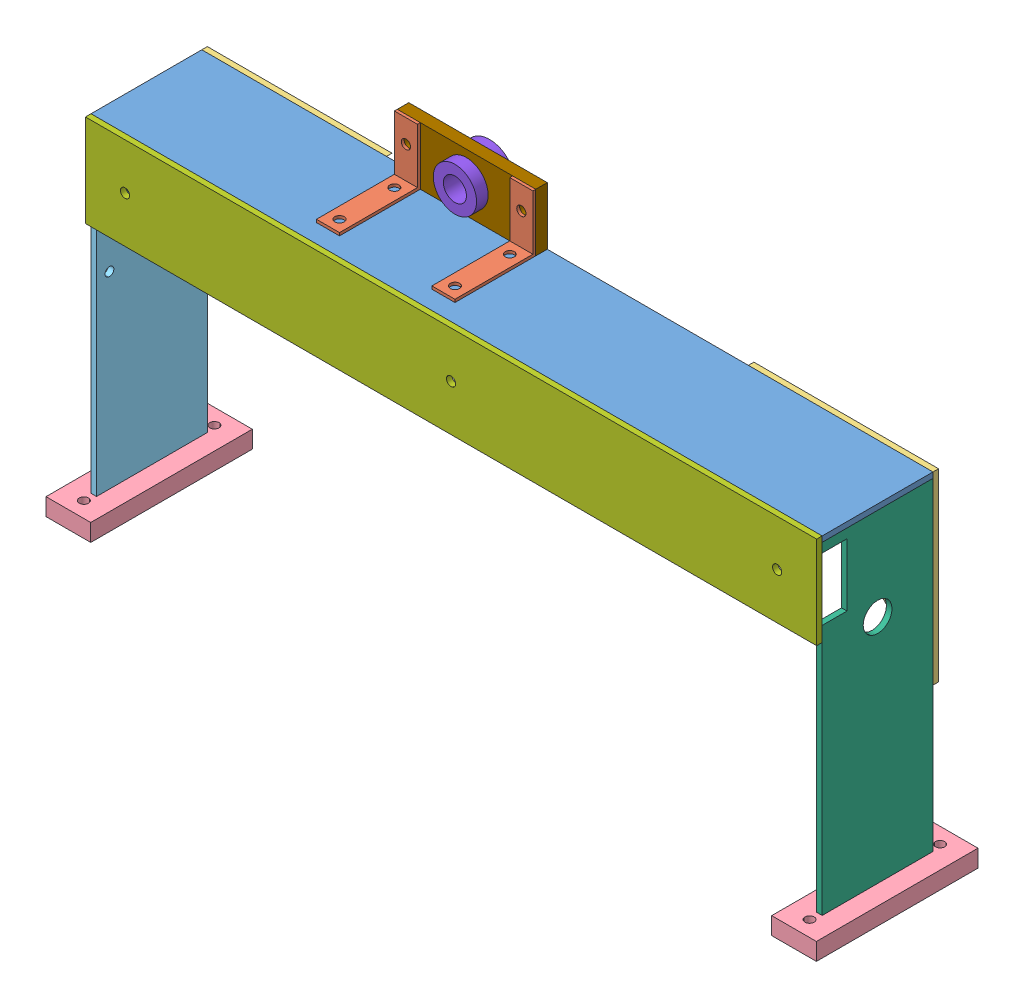
SolidWorks assembly Recognizer, configuration Default. Lengths in mm.
Overall size (423.85 222.12 88.9).
12 component instances, 9 part files, 31 mates.
Components (placement in the parent):
- Recognizer top-2: Recognizer top [Default] at (-162.9325 -9.8892 -49.3022) x (1 0 0) z (0 -1 0) size (402.29 60.96 3.05)
- Recognizer top bracket-2: Recognizer top bracket [Default] at (-49.0599 -9.8892 1.4978) x (0 0 -1) z (1 0 0) size (44.45 31.75 12.7)
- Recognizer top bracket-3: Recognizer top bracket [Default] at (14.4401 -9.8892 1.4978) x (0 0 -1) z (1 0 0) size (44.45 31.75 12.7)
- Recognizer bracket-1: Recognizer bracket [Default] at (239.3527 -111.4892 -49.3022) x (-1 0 0) z (0 0 -1) size (101.6 101.6 3.05)
- Recognizer bracket-2: Recognizer bracket [Default] at (-162.9325 -111.4892 -52.3502) size (101.6 101.6 3.05)
- Recognizer foot-1: Recognizer foot [Default] at (225.5224 -200.2622 25.6278) size (24.61 9.53 88.9)
- Recognizer foot-2: Recognizer foot [Default] at (-173.7148 -200.2622 25.6278) size (24.61 9.53 88.9)
- Recognizer stepper arm-3: Recognizer stepper arm [Default] at (-159.8845 -190.7372 -49.3022) x (0 0 1) z (-1 0 0) size (60.96 177.8 3.05)
- Recognizer regular arm-1: Recognizer regular arm [Default] at (236.3047 -190.7372 11.6578) x (0 0 -1) z (1 0 0) size (60.96 177.8 3.05)
- Recognizer back plate-1: Recognizer back plate [Default] at (-162.9325 -60.6892 11.6578) size (402.29 50.8 3.05)
- ACME nut fast travel-1: ACME nut fast travel [Default] at (-10.9599 5.9858 -55.6522) x (1 0 0) z (0 -1 0) size (28.45 19.05 28.45)
- Recognizer nut plate-3: Recognizer nut plate [Default] at (-49.0599 -9.8892 -49.3022) size (76.2 31.75 6.35)
Mates (geometry in assembly coordinates):
- Coincident7: coincident anti-aligned: plane of Recognizer top-2 through (-162.9325 -9.8892 -49.3022) normal (0 1 0); plane of Recognizer top bracket-2 through (-36.3599 -9.8892 1.4978) normal (0 -1 0)
- Coincident14: coincident anti-aligned: plane of Recognizer top-2 through (-162.9325 -9.8892 -49.3022) normal (0 1 0); plane of Recognizer top bracket-3 through (27.1401 -9.8892 1.4978) normal (0 -1 0)
- Coincident26: coincident aligned: plane of Recognizer top-2 through (-162.9325 -9.8892 -49.3022) normal (0 1 0); plane of Recognizer bracket-1 through (239.3527 -9.8892 -52.3502) normal (0 1 0)
- Coincident27: coincident anti-aligned: plane of Recognizer top-2 through (-162.9325 -12.9372 -49.3022) normal (0 0 -1); plane of Recognizer bracket-2 through (-162.9325 -111.4892 -49.3022) normal (0 0 1)
- Coincident29: coincident aligned: plane of Recognizer top-2 through (-162.9325 -9.8892 -49.3022) normal (0 1 0); plane of Recognizer bracket-2 through (-162.9325 -9.8892 -49.3022) normal (0 1 0)
- Coincident40: coincident anti-aligned: plane of Recognizer bracket-2 through (-162.9325 -111.4892 -49.3022) normal (0 0 1); plane of Recognizer stepper arm-3 through (-162.9325 -190.7372 -49.3022) normal (0 0 -1)
- Coincident42: coincident anti-aligned: plane of Recognizer foot-2 through (-173.7148 -190.7372 25.6278) normal (0 1 0); plane of Recognizer stepper arm-3 through (-162.9325 -190.7372 -49.3022) normal (0 -1 0)
- Coincident51: coincident aligned: plane of Recognizer bracket-1 through (239.3527 -111.4892 -52.3502) normal (1 0 0); plane of Recognizer regular arm-1 through (239.3527 -190.7372 11.6578) normal (1 0 0)
- Coincident52: coincident anti-aligned: plane of Recognizer bracket-1 through (239.3527 -111.4892 -49.3022) normal (0 0 1); plane of Recognizer regular arm-1 through (239.3527 -190.7372 -49.3022) normal (0 0 -1)
- Coincident55: coincident anti-aligned: plane of Recognizer foot-1 through (225.5224 -190.7372 25.6278) normal (0 1 0); plane of Recognizer regular arm-1 through (239.3527 -190.7372 11.6578) normal (0 -1 0)
- Coincident56: coincident anti-aligned: plane of Recognizer top-2 through (-162.9325 -12.9372 -49.3022) normal (0 0 -1); plane of Recognizer bracket-1 through (239.3527 -111.4892 -49.3022) normal (0 0 1)
- Coincident57: coincident aligned: plane of Recognizer top-2 through (-162.9325 -12.9372 -49.3022) normal (-1 0 0); plane of Recognizer stepper arm-3 through (-162.9325 -190.7372 -49.3022) normal (-1 0 0)
- Coincident58: coincident anti-aligned: plane of Recognizer top-2 through (-162.9325 -12.9372 -49.3022) normal (0 -1 0); plane of Recognizer stepper arm-3 through (-162.9325 -12.9372 -49.3022) normal (0 1 0)
- Coincident59: coincident aligned: plane of Recognizer bracket-2 through (-162.9325 -111.4892 -49.3022) normal (-1 0 0); plane of Recognizer stepper arm-3 through (-162.9325 -190.7372 -49.3022) normal (-1 0 0)
- Coincident60: coincident aligned: plane of Recognizer top-2 through (239.3527 -12.9372 -49.3022) normal (1 0 0); plane of Recognizer regular arm-1 through (239.3527 -190.7372 11.6578) normal (1 0 0)
- Coincident62: coincident aligned: plane of Recognizer stepper arm-3 through (-162.9325 -190.7372 -49.3022) normal (-1 0 0); plane of Recognizer back plate-1 through (-162.9325 -60.6892 14.7058) normal (-1 0 0)
- Coincident63: coincident aligned: plane of Recognizer top-2 through (-162.9325 -9.8892 -49.3022) normal (0 1 0); plane of Recognizer back plate-1 through (-162.9325 -9.8892 14.7058) normal (0 1 0)
- Coincident64: coincident anti-aligned: plane of Recognizer top-2 through (-162.9325 -12.9372 11.6578) normal (0 0 1); plane of Recognizer back plate-1 through (-162.9325 -60.6892 11.6578) normal (0 0 -1)
- Coincident65: coincident anti-aligned: plane of Recognizer top-2 through (-162.9325 -12.9372 -49.3022) normal (0 -1 0); plane of Recognizer regular arm-1 through (239.3527 -12.9372 11.6578) normal (0 1 0)
- Coincident67: coincident anti-aligned: plane of Recognizer foot-2 through (-162.9325 -197.2142 -49.3022) normal (0 0 1); plane of Recognizer stepper arm-3 through (-162.9325 -190.7372 -49.3022) normal (0 0 -1)
- Coincident68: coincident anti-aligned: plane of Recognizer foot-2 through (-162.9325 -197.2142 -49.3022) normal (1 0 0); plane of Recognizer stepper arm-3 through (-162.9325 -190.7372 -49.3022) normal (-1 0 0)
- Coincident69: coincident anti-aligned: plane of Recognizer foot-1 through (239.3527 -197.2142 -49.3022) normal (-1 0 0); plane of Recognizer regular arm-1 through (239.3527 -190.7372 11.6578) normal (1 0 0)
- Coincident70: coincident anti-aligned: plane of Recognizer foot-1 through (236.3047 -197.2142 -49.3022) normal (0 0 1); plane of Recognizer regular arm-1 through (239.3527 -190.7372 -49.3022) normal (0 0 -1)
- Concentric18: concentric aligned: circle of Recognizer top bracket-3; circle of Recognizer nut plate-3
- Concentric19: concentric aligned: circle of Recognizer top bracket-2; circle of Recognizer nut plate-3
- Coincident75: coincident anti-aligned: plane of Recognizer top bracket-2 through (-36.3599 -9.8892 -42.9522) normal (0 0 -1); plane of Recognizer nut plate-3 through (-49.0599 -9.8892 -42.9522) normal (0 0 1)
- Concentric20: concentric anti-aligned: cylinder of ACME nut fast travel-1 through (-10.9599 5.9858 -55.6522) axis (0 0 1) radius 11.8999; cylinder of Recognizer nut plate-3 through (-10.9599 5.9858 -42.9522) axis (0 0 -1) radius 11.8999
- Coincident76: coincident anti-aligned: plane of ACME nut fast travel-1 through (3.2641 5.9858 -49.3022) normal (0 0 1); plane of Recognizer nut plate-3 through (-49.0599 -9.8892 -49.3022) normal (0 0 -1)
- Concentric21: concentric aligned: circle of Recognizer top bracket-3; circle of Recognizer nut plate-3
- Coincident78: coincident anti-aligned: plane of Recognizer top bracket-3 through (27.1401 -9.8892 -42.9522) normal (0 0 -1); plane of Recognizer nut plate-3 through (-49.0599 -9.8892 -42.9522) normal (0 0 1)
- Coincident80: coincident aligned: plane of Recognizer top-2 through (-162.9325 -12.9372 -49.3022) normal (0 0 -1); plane of Recognizer nut plate-3 through (-49.0599 -9.8892 -49.3022) normal (0 0 -1)
